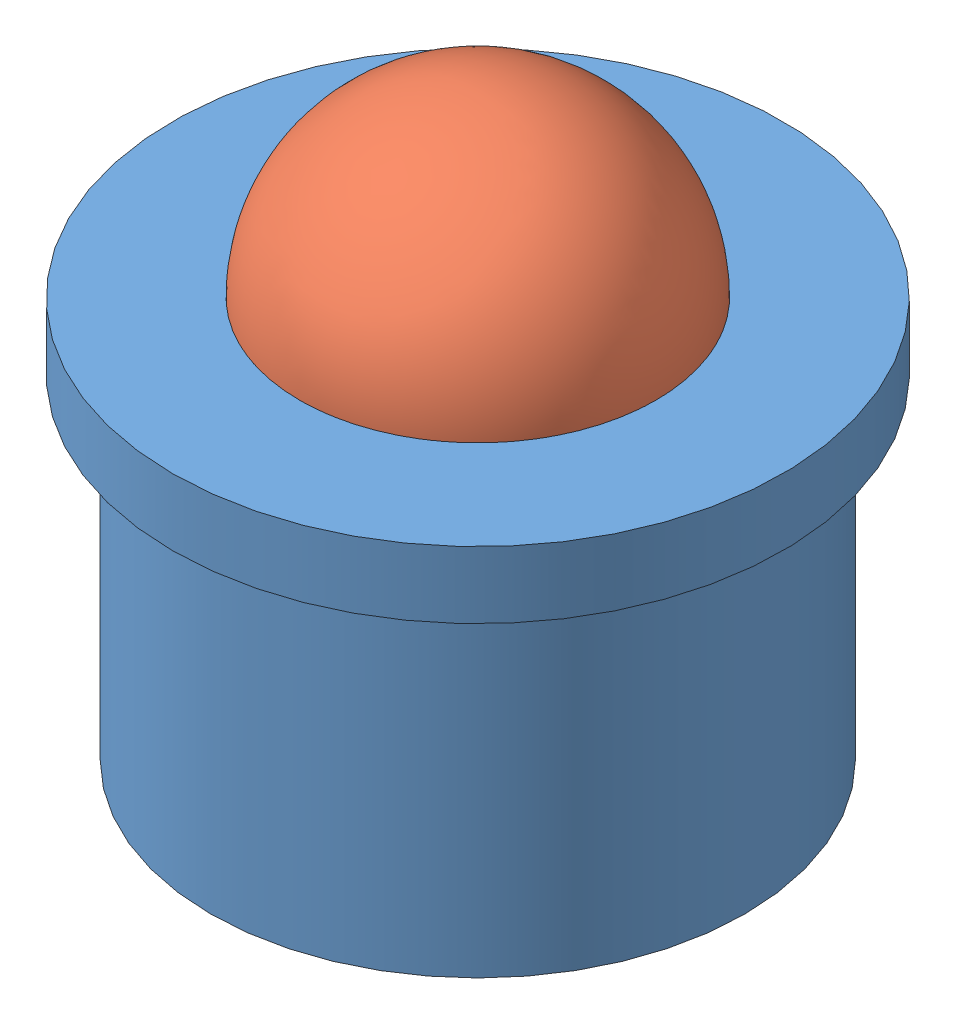
SolidWorks assembly 10_Ball_Transfer, configuration Default. Lengths in mm.
Overall size (21.59 13.76 21.59).
2 component instances, 2 part files, 1 mates.
Components (placement in the parent):
- 09_Ball_Holder-1: 09_Ball_Holder [Default] at (19.6556 -3.653 -11.1258) size (21.59 7.11 21.59)
- 08_Ball-1: 08_Ball [Default] at (19.6556 5.872 -11.1258) size (8.47 8.47 8.47)
Mates (geometry in assembly coordinates):
- Concentric1: concentric: sphere of 09_Ball_Holder-1; sphere of 08_Ball-1
